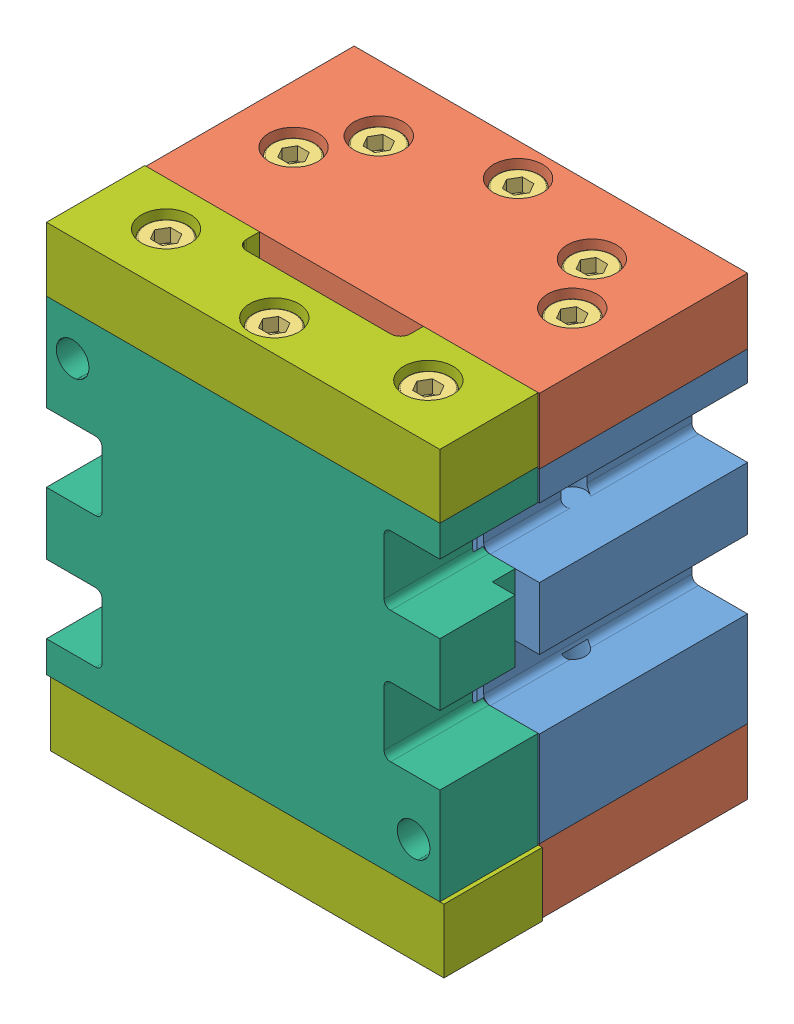
SolidWorks assembly Сборка матрицы, configuration По умолчанию. Lengths in mm.
Overall size (121.25 139 93.5).
28 component instances, 7 part files, 3 mates.
Components (placement in the parent):
- Матрица в сборе-1: Матрица в сборе [По умолчанию] at origin size (120 139 88.5)
  - Матрица-1: Матрица [По умолчанию] at origin size (120 99 63.5)
  - Боковина пресс-формы-1: Боковина пресс-формы [По умолчанию] at (0 -49.5 31.75) x (1 0 0) z (0 -1 0) size (120 63.5 20)
  - socket head cap screw_iso-1: socket head cap screw_iso [ISO 4762 M8 x 16 - 16N] at (-42.5 -67.5 36) x (0 1 0) z (0 0 1) size (24 13 13)
  - socket head cap screw_iso-2: socket head cap screw_iso [ISO 4762 M8 x 16 - 16N] at (-32.5 -67.5 20) x (0 1 0) z (0 0 1) size (24 13 13)
  - socket head cap screw_iso-3: socket head cap screw_iso [ISO 4762 M8 x 16 - 16N] at (0 -67.5 10) x (0 1 0) z (0 0 1) size (24 13 13)
  - socket head cap screw_iso-4: socket head cap screw_iso [ISO 4762 M8 x 16 - 16N] at (32.5 -67.5 20) x (0 1 0) z (0 0 1) size (24 13 13)
  - socket head cap screw_iso-5: socket head cap screw_iso [ISO 4762 M8 x 16 - 16N] at (42.5 -67.5 36) x (0 1 0) z (0 0 1) size (24 13 13)
  - socket head cap screw_iso-11: socket head cap screw_iso [ISO 4762 M8 x 16 - 16N] at (-42.5 67.5 36) x (0 -1 0) z (0 0 1) size (24 13 13)
  - socket head cap screw_iso-12: socket head cap screw_iso [ISO 4762 M8 x 16 - 16N] at (-32.5 67.5 20) x (0 -1 0) z (0 0 1) size (24 13 13)
  - socket head cap screw_iso-13: socket head cap screw_iso [ISO 4762 M8 x 16 - 16N] at (0 67.5 10) x (0 -1 0) z (0 0 1) size (24 13 13)
  - socket head cap screw_iso-14: socket head cap screw_iso [ISO 4762 M8 x 16 - 16N] at (32.5 67.5 20) x (0 -1 0) z (0 0 1) size (24 13 13)
  - socket head cap screw_iso-15: socket head cap screw_iso [ISO 4762 M8 x 16 - 16N] at (42.5 67.5 36) x (0 -1 0) z (0 0 1) size (24 13 13)
  - Боковина пресс-формы-3: Боковина пресс-формы [По умолчанию] at (0 49.5 31.75) x (-1 0 0) z (0 1 0) size (120 63.5 20)
  - КОнус-1: КОнус [По умолчанию] at (-52.375 37.5 33.5) x (0 0 1) z (-0.953769 -0.300541 0) size (55 10 10)
  - КОнус-2: КОнус [По умолчанию] at (51.625 -37.5 33.5) x (0 0 1) z (-0.599492 0.800381 0) size (55 10 10)
  - ВТулка-1: ВТулка [По умолчанию] at (0 27 30) x (0 0 1) z (-0.845392 0.534146 0) size (36.5 12 12)
  - ВТулка-2: ВТулка [По умолчанию] at (0 -27 30) x (0 0 1) z (-0.844306 0.535861 0) size (36.5 12 12)
- Сборка пуансона-1: Сборка пуансона [По умолчанию] at (-60.375 -50 63.5) size (121.25 139 30.34)
  - Пуансон-1: Пуансон [По умолчанию] at origin size (120 100 30)
  - Боковина Пуансона-1: Боковина Пуансона [По умолчанию] at (121.25 0 30) x (-1 0 0) z (0 -1 0) size (120 30.34 139)
  - Боковина Пуансона-2: Боковина Пуансона [По умолчанию] at (0 100 30) x (1 0 0) z (0 1 0) size (120 30.34 139)
  - socket head cap screw_iso-2: socket head cap screw_iso [ISO 4762 M8 x 16 - 16N] at (101.25 -17.5 13.5) x (0 1 0) z (0 0 1) size (24 13 13)
  - socket head cap screw_iso-3: socket head cap screw_iso [ISO 4762 M8 x 16 - 16N] at (61.25 -17.5 20.5) x (0 1 0) z (0 0 1) size (24 13 13)
  - socket head cap screw_iso-4: socket head cap screw_iso [ISO 4762 M8 x 16 - 16N] at (21.25 -17.5 13.5) x (0 1 0) z (0 0 1) size (24 13 13)
  - socket head cap screw_iso-5: socket head cap screw_iso [ISO 4762 M8 x 16 - 16N] at (20 117.5 13.5) x (0 -1 0) z (0 0 1) size (24 13 13)
  - socket head cap screw_iso-6: socket head cap screw_iso [ISO 4762 M8 x 16 - 16N] at (60 117.5 20.5) x (0 -1 0) z (0 0 1) size (24 13 13)
  - socket head cap screw_iso-7: socket head cap screw_iso [ISO 4762 M8 x 16 - 16N] at (100 117.5 13.5) x (0 -1 0) z (0 0 1) size (24 13 13)
Mates (geometry in assembly coordinates):
- Концентричный1: concentric aligned: cylinder of Матрица в сборе-1/КОнус-1 through (-52.375 37.5 33.5) axis (0 0 -1) radius 5; cylinder of Сборка пуансона-1/Пуансон-1 through (-52.375 37.5 113.5) axis (0 0 -1) radius 5
- Концентричный2: concentric aligned: cylinder of Матрица в сборе-1/КОнус-2 through (51.625 -37.5 33.5) axis (0 0 -1) radius 5; cylinder of Сборка пуансона-1/Пуансон-1 through (51.625 -37.5 113.5) axis (0 0 -1) radius 5
- Граничное расстояние1: limit distance = 0 mm anti-aligned: plane of Сборка пуансона-1/Пуансон-1 through (-60.375 -50 63.5) normal (0 0 -1); plane of Матрица в сборе-1/Матрица-1 through (0 0 63.5) normal (0 0 1)
